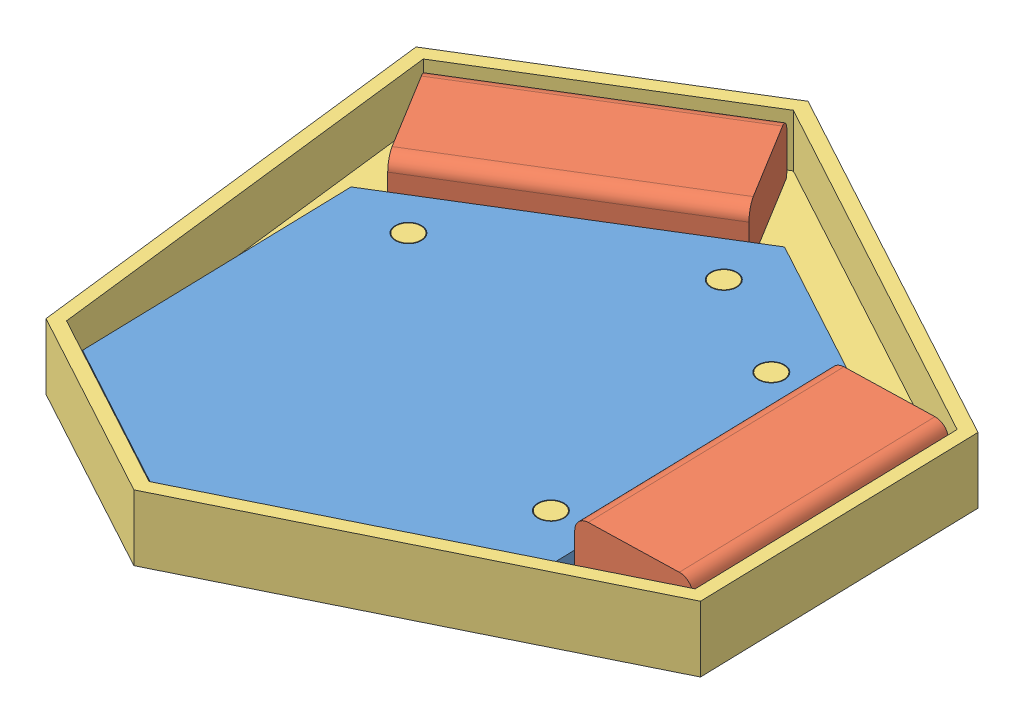
SolidWorks assembly device, configuration Default. Lengths in mm.
Overall size (90.5 6.41 88.54).
4 component instances, 3 part files, 7 mates.
Components (placement in the parent):
- pcb-1: pcb [Default] at (-31.3462 11.0026 -43.7375) x (-0.878863 0 -0.477074) z (-0.477074 0 0.878863) size (46.99 1.57 49.49)
- battery_110mAh-3: battery_110mAh [Default] at (-26.1643 9.7337 -101.8396) x (0.999655 0 -0.026273) z (0.026273 0 0.999655) size (11.13 5.78 25.4)
- battery_110mAh-4: battery_110mAh [Default] at (-50.8449 9.7337 -116.1599) x (0.522581 0 0.85259) z (-0.85259 0 0.522581) size (11.13 5.78 25.4)
- case_bottom-1: case_bottom [Default] at (-51.5801 7.5228 -87.3301) x (0.878863 0 0.477074) z (-0.477074 0 0.878863) size (68.47 6.35 63.58)
Mates (geometry in assembly coordinates):
- Coincident5: coincident anti-aligned: plane of pcb-1 through (-29.1774 9.4278 -43.7945) normal (0.999655 0 -0.026273); plane of battery_110mAh-3 through (-30.0324 9.4278 -76.3291) normal (-0.999655 0 0.026273)
- Coincident6: coincident aligned: line of pcb-1 through (-29.9582 9.4278 -73.5043) axis (-0.026273 0 -0.999655); line of battery_110mAh-3 through (-30.0324 9.4278 -76.3291) axis (-0.026273 0 -0.999655)
- Coincident8: coincident anti-aligned: plane of pcb-1 through (-65.4959 9.4278 -99.4526) normal (-0.522581 0 -0.85259); plane of battery_110mAh-4 through (-69.0579 12.6663 -97.2693) normal (0.522581 0 0.85259)
- Coincident9: coincident anti-aligned: line of pcb-1 through (-45.269 9.4278 -111.8503) axis (-0.85259 0 0.522581); line of battery_110mAh-4 through (-69.0579 9.4278 -97.2693) axis (0.85259 0 -0.522581)
- Coincident11: coincident anti-aligned: plane of pcb-1 through (-31.3462 9.4278 -43.7375) normal (0 -1 0); plane of case_bottom-1 through (-51.5801 9.4278 -87.3301) normal (0 1 0)
- Concentric1: concentric anti-aligned: circle of pcb-1; circle of case_bottom-1
- Concentric2: concentric anti-aligned: circle of pcb-1; circle of case_bottom-1
